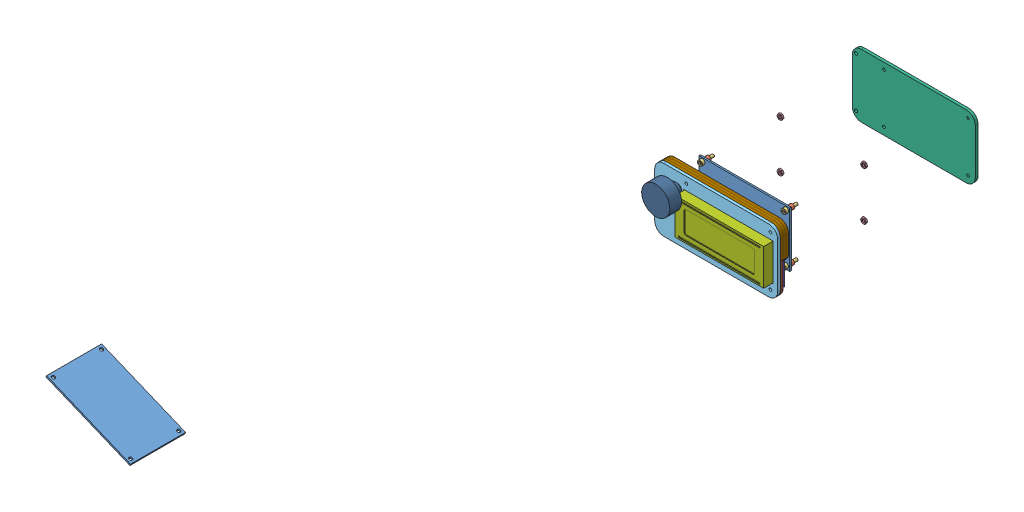
SolidWorks assembly Printrboard with screws, configuration Default. Lengths in mm.
Overall size (297.6 79.39 734.66).
23 component instances, 11 part files, 45 mates.
Components (placement in the parent):
- Printrboard1-1: Printrboard1 [Default] at (-125.038 -9.1989 77.5932) size (100.5 62.4 4.3)
- Acrilyc 5mm washer-1: Acrilyc 5mm washer [Default] at (-502.288 49.3511 72.5932) x (0 -1 0) z (0 0 1) size (5.2 5.2 5)
- Acrilyc 5mm washer-2: Acrilyc 5mm washer [Default] at (-502.288 -3.9489 72.5932) x (0 -1 0) z (0 0 1) size (5.2 5.2 5)
- Acrilyc 5mm washer-3: Acrilyc 5mm washer [Default] at (252.212 -6.8489 72.5932) x (0 1 0) z (0 0 1) size (5.2 5.2 5)
- Acrilyc 5mm washer-4: Acrilyc 5mm washer [Default] at (252.212 46.4511 72.5932) x (0 1 0) z (0 0 1) size (5.2 5.2 5)
- socket head cap screw_iso2-1: socket head cap screw_iso2 [ISO 4762 M3 x 12 --- 12N] at (-171.288 -5.3989 82.3932) x (0 0 -1) z (-1 0 0) size (15 5.5 5.5)
- socket head cap screw_iso2-2: socket head cap screw_iso2 [ISO 4762 M3 x 12 --- 12N] at (-171.288 47.9011 82.3932) x (0 0 -1) z (-1 0 0) size (15 5.5 5.5)
- socket head cap screw_iso2-3: socket head cap screw_iso2 [ISO 4762 M3 x 12 --- 12N] at (-78.788 47.9011 82.3932) x (0 0 -1) z (-1 0 0) size (15 5.5 5.5)
- socket head cap screw_iso2-4: socket head cap screw_iso2 [ISO 4762 M3 x 12 --- 12N] at (-78.788 -5.3989 82.3932) x (0 0 -1) z (-1 0 0) size (15 5.5 5.5)
- hex thin nut chamfered gradeab_iso2-1: hex thin nut chamfered gradeab_iso2 [Hexagon Thin Nut ISO - 4035 - M3 - N] at (-171.288 -5.3989 -7.8) x (0 1 0) z (0 0 -1) size (5.5 6.35 1.8)
- hex thin nut chamfered gradeab_iso2-2: hex thin nut chamfered gradeab_iso2 [Hexagon Thin Nut ISO - 4035 - M3 - N] at (-78.788 -5.3989 -6) x (-0.866025 -0.5 0) z (0 0 1) size (5.5 6.35 1.8)
- hex thin nut chamfered gradeab_iso2-3: hex thin nut chamfered gradeab_iso2 [Hexagon Thin Nut ISO - 4035 - M3 - N] at (-171.288 47.9011 -6) x (-0.866025 -0.5 0) z (0 0 1) size (5.5 6.35 1.8)
- hex thin nut chamfered gradeab_iso2-4: hex thin nut chamfered gradeab_iso2 [Hexagon Thin Nut ISO - 4035 - M3 - N] at (-78.788 47.9011 -6) x (0 -1 0) z (0 0 1) size (5.5 6.35 1.8)
- Panel-1: Panel [Default] at (-124.9381 32.9991 109.4976) x (-1 0 0) z (0 -1 0) size (136.06 3 70)
- Panel back-1: Panel back [Default] at (-124.9381 32.9991 -109.1423) x (-1 0 0) z (0 0 -1) size (136.06 70 3)
- lcd-2: lcd [Default] at (-199.5064 -13.522 99.4976) x (1 0 0) z (0 -1 0) size (98 15 60)
- Part2^Panel-1: Part2^Panel [Default] at (-66.8295 126.8924 99.4976) x (-1 0 0) z (0 0 -1) size (128.47 69.61 8)
- Part1^Panel2-1: Part1^Panel2 [Default] at (-161.5064 -88.8208 106.4976) x (-1 0 0) z (0 0 -1) size (136.06 35.69 3)
- Part1^Panel2-2: Part1^Panel2 [Default] at (-161.5064 -88.8208 103.4976) x (-1 0 0) z (0 0 -1) size (136.06 35.69 3)
- Part1^Panel2-3: Part1^Panel2 [Default] at (-161.5064 -88.8208 100.4976) x (-1 0 0) z (0 0 -1) size (136.06 35.69 3)
- Copy (2) of Part3^Printrboard with screws-1: Copy (2) of Part3^Printrboard with screws [Default] at (-161.5064 -88.8208 104.4976) size (31.09 31.09 29) (virtual)
- Part1^Pane3-1: Part1^Pane3 [Default] at (-161.5064 -88.8208 106.4976) x (-1 0 0) z (0 0 -1) size (136.06 54.79 3)
- Printrboard1-2: Printrboard1 [Default] at (-307.4809 3.8557 561.6171) x (0.924225 -0.381849 0) z (-0.381849 -0.924225 0) size (100.5 62.4 4.3)
Mates (geometry in assembly coordinates):
- Concentric40052: concentric aligned: cylinder of Printrboard1-1 through (-171.288 -5.3989 77.5922) axis (0 0 1) radius 1.75; cylinder of socket head cap screw_iso2-1 through (-171.288 -5.3989 114.1432) axis (0 0 1) radius 2.75
- Coincident787159: coincident anti-aligned: plane of Printrboard1-1 through (-175.288 -9.1989 79.3932) normal (0 0 1); plane of socket head cap screw_iso2-1 through (-171.288 -8.1489 79.3932) normal (0 0 -1)
- Concentric40053: concentric aligned: cylinder of Printrboard1-1 through (-171.288 47.9011 77.5922) axis (0 0 1) radius 1.75; cylinder of socket head cap screw_iso2-2 through (-171.288 47.9011 114.1432) axis (0 0 1) radius 2.75
- Coincident787160: coincident anti-aligned: plane of Printrboard1-1 through (-175.288 -9.1989 79.3932) normal (0 0 1); plane of socket head cap screw_iso2-2 through (-171.288 45.1511 79.3932) normal (0 0 -1)
- Concentric40054: concentric aligned: cylinder of Printrboard1-1 through (-78.788 47.9011 77.5922) axis (0 0 1) radius 1.75; cylinder of socket head cap screw_iso2-3 through (-78.788 47.9011 114.1432) axis (0 0 1) radius 2.75
- Coincident787161: coincident anti-aligned: plane of Printrboard1-1 through (-175.288 -9.1989 79.3932) normal (0 0 1); plane of socket head cap screw_iso2-3 through (-78.788 45.1511 79.3932) normal (0 0 -1)
- Concentric40055: concentric aligned: cylinder of Printrboard1-1 through (-78.788 -5.3989 77.5922) axis (0 0 1) radius 1.75; cylinder of socket head cap screw_iso2-4 through (-78.788 -5.3989 114.1432) axis (0 0 1) radius 2.75
- Coincident787162: coincident anti-aligned: plane of Printrboard1-1 through (-175.288 -9.1989 79.3932) normal (0 0 1); plane of socket head cap screw_iso2-4 through (-78.788 -8.1489 79.3932) normal (0 0 -1)
- Concentric401122: concentric anti-aligned: cylinder of socket head cap screw_iso2-1 through (-171.288 -5.3989 114.1432) axis (0 0 1) radius 1.5; cylinder of hex thin nut chamfered gradeab_iso2-1 through (-171.288 -5.3989 -6) axis (0 0 -1) radius 1.25
- Concentric401119: concentric aligned: cylinder of socket head cap screw_iso2-4 through (-78.788 -5.3989 114.1432) axis (0 0 1) radius 1.5; cylinder of hex thin nut chamfered gradeab_iso2-2 through (-78.788 -5.3989 -31.0375) axis (0 0 1) radius 1.5
- Concentric401120: concentric aligned: cylinder of socket head cap screw_iso2-2 through (-171.288 47.9011 114.1432) axis (0 0 1) radius 1.5; cylinder of hex thin nut chamfered gradeab_iso2-3 through (-171.288 47.9011 -31.0375) axis (0 0 1) radius 1.5
- Concentric401121: concentric aligned: cylinder of socket head cap screw_iso2-3 through (-78.788 47.9011 114.1432) axis (0 0 1) radius 1.5; cylinder of hex thin nut chamfered gradeab_iso2-4 through (-78.788 47.9011 -31.0375) axis (0 0 1) radius 1.5
- Coincidente1: coincident: plane of Panel-1 through (58.1909 88.3774 85.8438) normal (0 1 0); plane of lcd-2 through (-63.5064 -9.522 106.4976) normal (0 0 1)
- Concêntrico5: concentric aligned: cylinder of Panel-1 through (-66.0064 47.978 106.4976) axis (0 0 1) radius 1.5; cylinder of Panel back-1 through (-66.0064 47.978 -112.1423) axis (0 0 1) radius 1.3
- Concentric4: concentric anti-aligned: circle of Panel-1; circle of lcd-2
- Concentric5: concentric anti-aligned: circle of Panel-1; circle of lcd-2
- Coincident9: coincident anti-aligned: plane of Panel-1 through (-124.9381 32.9991 106.4976) normal (0 0 -1); plane of lcd-2 through (-63.5064 -9.522 106.4976) normal (0 0 1)
- Coincident10: coincident anti-aligned: plane of Panel-1 through (-124.9381 32.9991 106.4976) normal (0 0 -1); plane of Part1^Panel2-1 through (-67.9698 -5.022 106.4976) normal (0 0 1)
- Concentric7: concentric aligned: cylinder of Panel-1 through (-184.033 44.978 106.4976) axis (0 0 1) radius 10; cylinder of Part1^Panel2-1 through (-184.033 44.978 103.4976) axis (0 0 1) radius 10
- Concentric8: concentric aligned: cylinder of Panel-1 through (-184.033 44.978 106.4976) axis (0 0 1) radius 10; cylinder of Part1^Panel2-2 through (-184.033 44.978 100.4976) axis (0 0 1) radius 10
- Concentric9: concentric aligned: cylinder of Panel-1 through (-184.033 44.978 106.4976) axis (0 0 1) radius 10; cylinder of Part1^Panel2-3 through (-184.033 44.978 97.4976) axis (0 0 1) radius 10
- Concentric6: concentric anti-aligned: cylinder of Panel back-1 through (-159.0064 47.978 -112.1423) axis (0 0 1) radius 1.5; cylinder of lcd-2 through (-159.0064 47.978 106.4976) axis (0 0 -1) radius 1.75
- Coincident18: coincident aligned: plane of Panel back-1 through (-57.9698 44.978 -112.1423) normal (1 0 0); plane of Part1^Panel2-3 through (-57.9698 44.978 97.4976) normal (1 0 0)
- Coincident19: coincident anti-aligned: plane of Panel back-1 through (-184.033 44.978 55.7798) normal (0 0 1); plane of Part1^Panel2-3 through (-67.9698 -5.022 55.7798) normal (0 0 -1)
- Coincident21: coincident aligned: plane of Panel back-1 through (-194.033 44.978 -112.1423) normal (-1 0 0); plane of Part1^Pane3-1 through (-194.033 -5.022 103.4976) normal (-1 0 0)
- Coincident12: coincident aligned: plane of lcd-2 through (-63.5064 50.478 106.4976) normal (1 0 0); plane of Part2^Panel-1 through (-63.5064 126.8924 96.4976) normal (1 0 0)
- Coincident13: coincident anti-aligned: plane of lcd-2 through (-63.5064 -9.522 104.4976) normal (0 0 -1); plane of Part2^Panel-1 through (-66.8295 126.8924 104.4976) normal (0 0 1)
- Coincident14: coincident aligned: plane of lcd-2 through (-63.5064 -9.522 106.4976) normal (0 -1 0); plane of Part2^Panel-1 through (-66.8295 -9.522 96.4976) normal (0 -1 0)
- Coincident16: coincident anti-aligned: plane of Part1^Panel2-1 through (-67.9698 -5.022 103.4976) normal (0 0 -1); plane of Part1^Panel2-2 through (-67.9698 -5.022 103.4976) normal (0 0 1)
- Concentric10: concentric aligned: cylinder of Part1^Panel2-1 through (-60.7209 20.3855 113.4976) axis (0 0 -1) radius 1.1001; cylinder of Part1^Pane3-1 through (-60.7209 20.3855 113.4976) axis (0 0 -1) radius 1.1001
- Concentric11: concentric aligned: cylinder of Part1^Panel2-1 through (-190.1786 36.8754 113.4976) axis (0 0 -1) radius 1.2952; cylinder of Part1^Pane3-1 through (-190.1786 36.8754 113.4976) axis (0 0 -1) radius 1.2952
- Coincident20: coincident aligned: plane of Part1^Panel2-1 through (-67.9698 -5.022 106.4976) normal (0 0 1); plane of Part1^Pane3-1 through (-67.9698 -5.022 106.4976) normal (0 0 1)
- Coincident17: coincident anti-aligned: plane of Part1^Panel2-2 through (-67.9698 -5.022 100.4976) normal (0 0 -1); plane of Part1^Panel2-3 through (-67.9698 -5.022 100.4976) normal (0 0 1)
- Concentric401123: concentric aligned: cylinder of Acrilyc 5mm washer-1 through (-171.288 47.9011 77.5932) axis (0 0 1) radius 1.6; cylinder of socket head cap screw_iso2-2 through (-171.288 47.9011 114.1432) axis (0 0 1) radius 1.5
- Concentric401124: concentric anti-aligned: cylinder of Acrilyc 5mm washer-4 through (-78.788 47.9011 77.5932) axis (0 0 -1) radius 2.6; cylinder of socket head cap screw_iso2-3 through (-78.788 47.9011 114.1432) axis (0 0 1) radius 1.5
- Concentric401125: concentric anti-aligned: cylinder of Acrilyc 5mm washer-3 through (-78.788 -5.3989 77.5932) axis (0 0 -1) radius 2.6; cylinder of socket head cap screw_iso2-4 through (-78.788 -5.3989 114.1432) axis (0 0 1) radius 1.5
- Concentric401126: concentric anti-aligned: cylinder of Acrilyc 5mm washer-2 through (-171.288 -5.3989 77.5932) axis (0 0 -1) radius 2.6; cylinder of socket head cap screw_iso2-1 through (-171.288 -5.3989 114.1432) axis (0 0 1) radius 1.5
- Coincident787163: coincident anti-aligned: plane of Printrboard1-1 through (-175.288 -9.1989 77.5932) normal (0 0 -1); plane of Acrilyc 5mm washer-4 through (-78.788 47.9011 77.5932) normal (0 0 1)
- Coincident787164: coincident anti-aligned: plane of Printrboard1-1 through (-175.288 -9.1989 77.5932) normal (0 0 -1); plane of Acrilyc 5mm washer-3 through (-78.788 -5.3989 77.5932) normal (0 0 1)
- Coincident787165: coincident anti-aligned: plane of Printrboard1-1 through (-175.288 -9.1989 77.5932) normal (0 0 -1); plane of Acrilyc 5mm washer-1 through (-171.288 47.9011 77.5932) normal (0 0 1)
- Coincident787167: coincident anti-aligned: plane of Printrboard1-1 through (-175.288 -9.1989 77.5932) normal (0 0 -1); plane of Acrilyc 5mm washer-2 through (-171.288 -5.3989 77.5932) normal (0 0 1)
- Concentric401127: concentric aligned: cylinder of Part1^Panel2-2 through (-60.7209 20.3855 110.4976) axis (0 0 -1) radius 1.1001; cylinder of Part1^Panel2-3 through (-60.7209 20.3855 107.4976) axis (0 0 -1) radius 1.1001
- Coincident787168: coincident anti-aligned: plane of Panel-1 through (-124.9381 32.9991 106.4976) normal (0 0 -1); plane of lcd-2 through (-63.5064 -9.522 106.4976) normal (0 0 1)
- Coincident787169: coincident anti-aligned: plane of Panel-1 through (-124.9381 32.9991 106.4976) normal (0 0 -1); plane of Part1^Pane3-1 through (-67.9698 -5.022 106.4976) normal (0 0 1)
- Coincident787171: coincident: plane of lcd-2 through (-63.5064 -9.522 104.4976) normal (0 0 -1); line of Part2^Panel-1 through (-159.0064 47.978 104.4976) axis (-1 0 0)
